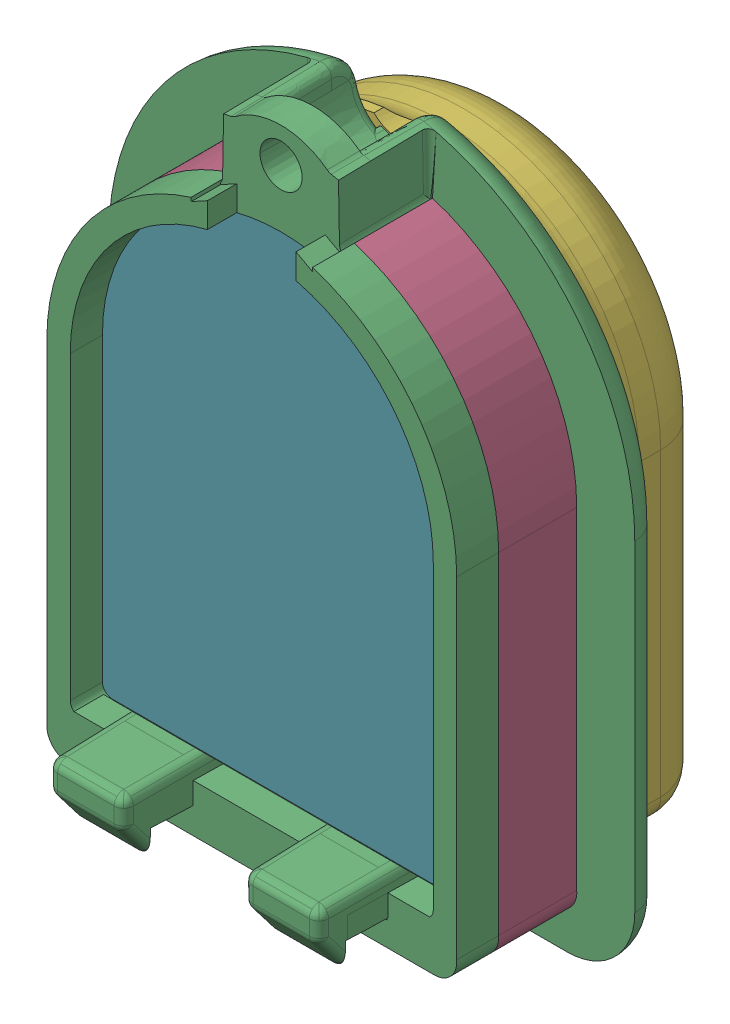
SolidWorks assembly Conti, configuration 默认. Lengths in mm.
Overall size (26.95 34.26 17.16).
6 component instances, 6 part files, 15 mates.
Components (placement in the parent):
- ContiOriginBody-1: ContiOriginBody [默认] at (-2.213 7.3799 -8.324) size (26.95 34.26 11.18)
- ContiTransBody-1: ContiTransBody [默认] at (-2.213 7.3799 -8.324) size (21.01 28.27 4)
- ContiInsideSKin-1: ContiInsideSKin [默认] at (-2.213 4.0799 -8.324) x (-1 0 0) z (0 0 -1) size (18.6 25.2 5.2)
- ContioutSkin-1: ContioutSkin [默认] at (-2.213 4.0799 -8.324) x (-1 0 0) z (0 0 -1) size (21.8 28.5 6)
- ContiLens-1: ContiLens [默认] at (-2.213 7.3799 -8.324) size (18.6 25.2 6)
- ConMarker-1: ConMarker [默认] at (-8.213 -6.5201 -13.524) size (13 20.5 0.4)
Mates (geometry in assembly coordinates):
- 重合1: coincident anti-aligned: plane of OriginBody-1 through (-2.213 7.3799 -6.824) normal (0 0 1); plane of 实体3-1 through (7.137 -9.7124 -6.824) normal (0 0 -1)
- 同心1: concentric aligned: cylinder of OriginBody-1 through (-2.213 7.3799 -0.674) axis (0 0 -1) radius 10.5; cylinder of 实体3-1 through (-2.213 7.3799 -0.674) axis (0 0 -1) radius 10.5
- 重合2: coincident aligned: plane of OriginBody-1 through (8.287 7.3799 -0.674) normal (1 0 0); plane of 实体3-1 through (8.287 7.3799 -0.674) normal (1 0 0)
- 重合3: coincident anti-aligned: plane of 实体3-1 through (-2.213 -8.5201 48.523) normal (0 1 0); plane of NewBoardlensnew-1 through (-11.513 -8.5201 -2.324) normal (0 -1 0)
- 同心2: concentric aligned: cylinder of 实体3-1 through (-2.213 7.3799 48.523) axis (0 0 -1) radius 9.3; cylinder of NewBoardlensnew-1 through (-2.213 7.3799 -2.324) axis (0 0 -1) radius 9.3
- 重合4: coincident aligned: plane of OriginBody-1 through (-2.2735 3.9424 -8.324) normal (0 0 -1); plane of NewBoardlensnew-1 through (-2.213 7.3799 -8.324) normal (0 0 -1)
- 重合5: coincident anti-aligned: plane of NewInsideSkin-1 through (-11.013 -8.0201 -8.324) normal (0 0 1); plane of NewBoardlensnew-1 through (-2.213 7.3799 -8.324) normal (0 0 -1)
- 平行1: parallel anti-aligned: line of OriginBody-1 through (-11.513 7.3799 -8.324) axis (0 -1 0); line of NewInsideSkin-1 through (-11.513 -8.0201 -8.324) axis (0 1 0)
- 同心3: concentric anti-aligned: circle of OriginBody-1; circle of NewInsideSkin-1
- 重合6: coincident anti-aligned: plane of NewInsideSkin-1 through (-11.013 -8.0201 -13.524) normal (0 0 -1); plane of outSkin-1 through (-11.013 -8.0201 -13.524) normal (0 0 1)
- 同心4: concentric aligned: cylinder of NewInsideSkin-1 through (-2.213 7.3799 -13.524) axis (0 0 1) radius 9.3; cylinder of outSkin-1 through (-2.213 7.3799 -13.524) axis (0 0 1) radius 9.3
- 平行2: parallel aligned: plane of NewInsideSkin-1 through (-11.013 -8.5201 -13.524) normal (0 -1 0); plane of outSkin-1 through (-11.013 -9.3201 -13.524) normal (0 -1 0)
- 重合10: coincident aligned: plane of ContiInsideSKin-1 through (-11.013 -8.0201 -13.524) normal (0 0 -1); plane of ConMarker-1 through (-8.213 -6.5201 -13.524) normal (0 0 -1)
- 宽度2: width anti-aligned: plane of ContiInsideSKin-1 through (-11.513 7.3799 -13.524) normal (-1 0 0); plane of ContiInsideSKin-1 through (7.087 -8.0201 -13.524) normal (1 0 0); plane of ConMarker-1 through (4.287 -6.5201 -13.124) normal (1 0 0); plane of ConMarker-1 through (-8.713 4.465 -13.524) normal (-1 0 0)
- 重合11: coincident: line of ContiInsideSKin-1 through (5.087 -6.5201 -13.524) axis (-1 0 0); plane of ConMarker-1 through (-8.213 -6.5201 -13.124) normal (0 -1 0)
